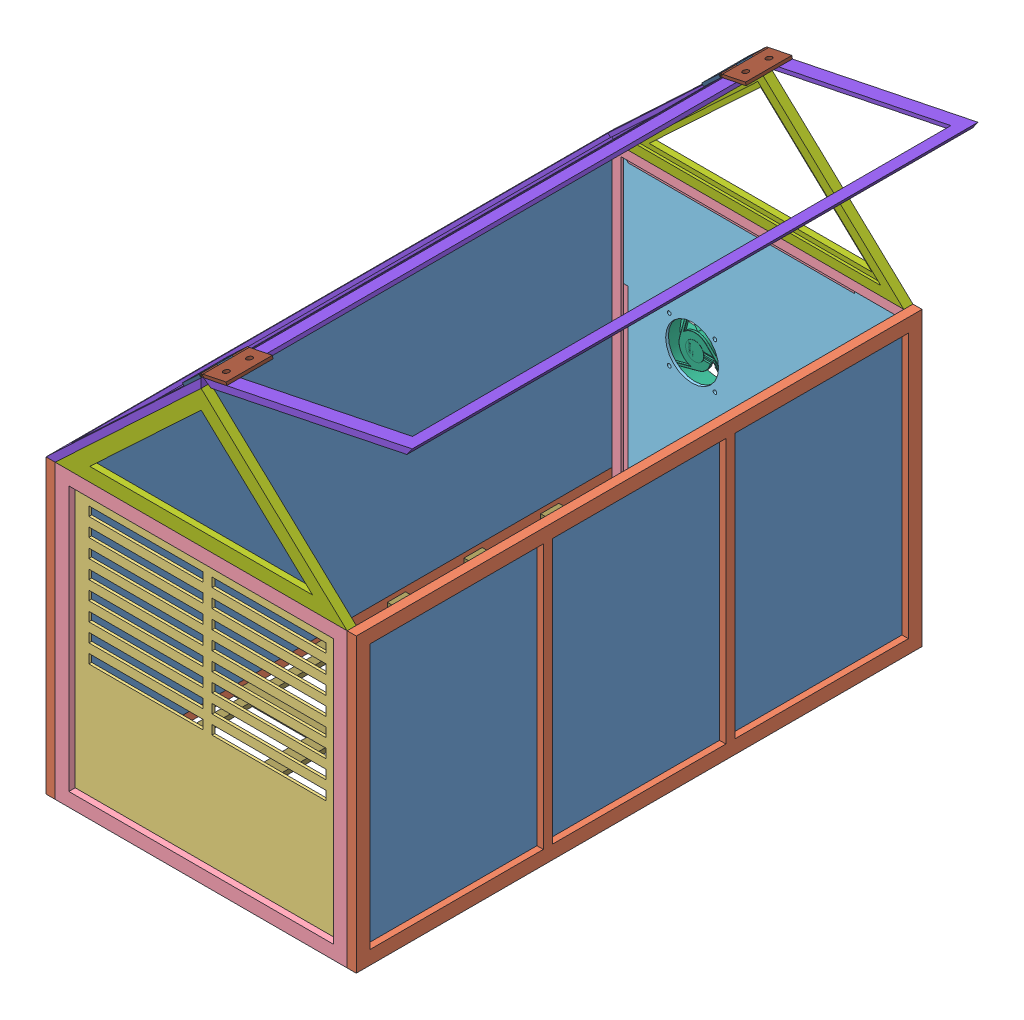
SolidWorks assembly Ensamblaje1, configuration Predeterminado. Lengths in mm.
Overall size (401.19 620.27 664.12).
23 component instances, 12 part files, 53 mates.
Components (placement in the parent):
- Cara lateral-1: Cara lateral [Predeterminado] at (-310 0 606) x (0 0 -1) z (-1 0 0) size (600 300 3)
- Marco lateral-1: Marco lateral [Predeterminado] at (-310 0 606) x (0 0 -1) z (-1 0 0) size (620 320 10)
- Cara Frontal-1: Cara Frontal [Predeterminado] at (0 0 606) x (-1 0 0) z (0 0 1) size (300 300 3)
- Marco Frontal y lateral-1: Marco Frontal y lateral [Predeterminado] at (0 0 606) x (-1 0 0) z (0 0 1) size (320 320 10)
- Marco Frontal y lateral-2: Marco Frontal y lateral [Predeterminado] at (-300 0 6) x (1 0 0) z (0 0 -1) size (320 320 10)
- Marco lateral-2: Marco lateral [Predeterminado] at (10 0 6) x (0 0 1) z (1 0 0) size (620 320 10)
- Cara lateral-2: Cara lateral [Predeterminado] at (13 0 606) x (0 0 -1) z (-1 0 0) size (600 300 3)
- Cara Posterior-1: Cara Posterior [Predeterminado] x (-1 0 0) z (0 0 1) size (300 300 3)
- fan 3inch-1: fan 3inch [Default] at (-75 -150 0) x (-1 0 0) z (0 -1 0) size (82.51 48.37 80)
- fan 3inch-3: fan 3inch [Default] at (-225 -150 0) x (-1 0 0) z (0 -1 0) size (82.51 48.37 80)
- Triangulo superior-1: Triangulo superior [Predeterminado] at (-310 10 606) size (320 150 10)
- Triangulo superior-2: Triangulo superior [Predeterminado] at (10 10 6) x (-1 0 0) z (0 0 -1) size (320 150 10)
- tapa superior-2: tapa superior [Predeterminado] at (-310 10 -4) size (170 160 620)
- tapa superior-3: tapa superior [Predeterminado] at (75.4274 209.9477 615.9039) x (-0.575939 -0.817492 0) z (0 0 -1) size (170 160 620)
- ESAMBLAJE-1: ESAMBLAJE [Predeterminado] at (-149.4075 172.3854 590.5039) x (-0.651352 -0.758775 0) z (0 0 1) size (50.37 22.76 50.9)
  - tornillo 3-1: tornillo 3 [Predeterminado] at (-0.1124 -0.1798 -25.4) size (1.52 1.52 50.8)
  - Placa 1-1: Placa 1 [Predeterminado] at (14.8242 -0.2436 0.0961) x (0 0 1) z (0.994353 -0.106126 0) size (50.8 3.3 29.21)
  - placa 2-1: placa 2 [Predeterminado] at (-12.7879 7.722 0) x (0 0 1) z (-0.790304 0.612716 0) size (50.8 3.3 29.21)
- ESAMBLAJE-2: ESAMBLAJE [Predeterminado] at (-149.4075 172.3854 21.3039) x (-0.651352 -0.758775 0) z (0 0 1) size (50.37 22.76 50.9)
  - tornillo 3-1: tornillo 3 [Predeterminado] at (-0.1124 -0.1798 -25.4) size (1.52 1.52 50.8)
  - Placa 1-1: Placa 1 [Predeterminado] at (14.8242 -0.2436 0.0961) x (0 0 1) z (0.994353 -0.106126 0) size (50.8 3.3 29.21)
  - placa 2-1: placa 2 [Predeterminado] at (-12.7879 7.722 0) x (0 0 1) z (-0.790304 0.612716 0) size (50.8 3.3 29.21)
- Matriz porta materas-1: Matriz porta materas [Predeterminado] at (-72 -240 554) x (0 0 -1) z (1 0 0) size (524 5 188)
Mates (geometry in assembly coordinates):
- Coincidente8: coincident anti-aligned: plane of Cara lateral-1 through (-313 0 6) normal (0 0 -1); plane of Marco lateral-1 through (-313 0 6) normal (0 0 1)
- Coincidente9: coincident anti-aligned: plane of Cara lateral-1 through (-313 0 606) normal (0 1 0); plane of Marco lateral-1 through (-313 0 606) normal (0 -1 0)
- Coincidente10: coincident anti-aligned: plane of Cara lateral-1 through (-313 0 606) normal (-1 0 0); plane of Marco lateral-1 through (-313 0 606) normal (1 0 0)
- Coincidente11: coincident anti-aligned: plane of Marco lateral-1 through (-310 0 606) normal (1 0 0); plane of Marco Frontal y lateral-1 through (-310 10 616) normal (-1 0 0)
- Coincidente12: coincident aligned: plane of Marco lateral-1 through (-320 10 616) normal (0 1 0); plane of Marco Frontal y lateral-1 through (10 10 616) normal (0 1 0)
- Coincidente13: coincident aligned: plane of Marco lateral-1 through (-320 10 616) normal (0 0 1); plane of Marco Frontal y lateral-1 through (0 0 616) normal (0 0 1)
- Coincidente14: coincident anti-aligned: plane of Marco lateral-1 through (-310 0 606) normal (1 0 0); plane of Marco Frontal y lateral-2 through (-310 10 -4) normal (-1 0 0)
- Coincidente15: coincident aligned: plane of Marco lateral-1 through (-320 10 616) normal (0 1 0); plane of Marco Frontal y lateral-2 through (-310 10 -4) normal (0 1 0)
- Coincidente16: coincident aligned: plane of Marco lateral-1 through (-320 10 -4) normal (0 0 -1); plane of Marco Frontal y lateral-2 through (-300 0 -4) normal (0 0 -1)
- Coincidente17: coincident anti-aligned: plane of Marco Frontal y lateral-1 through (10 10 616) normal (1 0 0); plane of Marco lateral-2 through (10 0 6) normal (-1 0 0)
- Coincidente18: coincident aligned: plane of Marco Frontal y lateral-2 through (-300 0 -4) normal (0 0 -1); plane of Marco lateral-2 through (20 10 -4) normal (0 0 -1)
- Coincidente19: coincident aligned: plane of Marco Frontal y lateral-2 through (-310 10 -4) normal (0 1 0); plane of Marco lateral-2 through (20 10 -4) normal (0 1 0)
- Coincidente20: coincident anti-aligned: plane of Cara Frontal-1 through (0 0 609) normal (0 1 0); plane of Marco Frontal y lateral-1 through (0 0 609) normal (0 -1 0)
- Coincidente21: coincident anti-aligned: plane of Cara Frontal-1 through (-300 0 609) normal (-1 0 0); plane of Marco Frontal y lateral-1 through (-300 0 609) normal (1 0 0)
- Coincidente22: coincident anti-aligned: plane of Cara Frontal-1 through (0 0 609) normal (0 0 1); plane of Marco Frontal y lateral-1 through (0 0 609) normal (0 0 -1)
- Coincidente23: coincident anti-aligned: plane of Marco lateral-2 through (13 0 6) normal (-1 0 0); plane of Cara lateral-2 through (13 0 606) normal (1 0 0)
- Coincidente24: coincident anti-aligned: plane of Marco lateral-2 through (13 -300 6) normal (0 1 0); plane of Cara lateral-2 through (10 -300 606) normal (0 -1 0)
- Coincidente25: coincident anti-aligned: plane of Marco lateral-2 through (13 0 6) normal (0 0 1); plane of Cara lateral-2 through (10 0 6) normal (0 0 -1)
- Coincidente26: coincident aligned: plane of Marco Frontal y lateral-2 through (-300 0 3) normal (0 0 1); plane of Cara Posterior-1 through (0 0 3) normal (0 0 1)
- Coincidente27: coincident anti-aligned: plane of Marco Frontal y lateral-2 through (0 0 3) normal (-1 0 0); plane of Cara Posterior-1 through (0 0 3) normal (1 0 0)
- Coincidente28: coincident anti-aligned: plane of Marco Frontal y lateral-2 through (-300 0 3) normal (0 -1 0); plane of Cara Posterior-1 through (0 0 3) normal (0 1 0)
- Concéntrica1: concentric aligned: circle of Cara Posterior-1; circle of fan 3inch-1
- Coincidente30: coincident aligned: plane of Cara Posterior-1 through (0 0 0) normal (0 0 1); plane of assembly through (0 0 0) normal (0 0 1)
- Coincidente31: coincident anti-aligned: plane of Cara Posterior-1 through (0 0 0) normal (0 -1 0); plane of assembly through (0 0 0) normal (0 1 0)
- Coincidente32: coincident anti-aligned: plane of Cara Posterior-1 through (0 0 0) normal (-1 0 0); plane of assembly through (0 0 0) normal (1 0 0)
- Coincidente33: coincident anti-aligned: plane of Cara Posterior-1 through (0 0 0) normal (0 0 -1); plane of fan 3inch-1 through (-35 -110 0) normal (0 0 1)
- Paralelo1: parallel aligned: plane of Marco Frontal y lateral-2 through (-310 -310 -4) normal (0 -1 0); plane of fan 3inch-1 through (-35 -190 -25.5) normal (0 -1 0)
- Concéntrica3: concentric anti-aligned: circle of Cara Posterior-1; circle of fan 3inch-3
- Coincidente39: coincident anti-aligned: plane of Cara Posterior-1 through (0 0 0) normal (0 0 -1); plane of fan 3inch-3 through (-185 -110 0) normal (0 0 1)
- Paralelo4: parallel aligned: plane of Marco Frontal y lateral-2 through (-310 -310 -4) normal (0 -1 0); plane of fan 3inch-3 through (-185 -190 -25.5) normal (0 -1 0)
- Coincidente40: coincident anti-aligned: plane of Marco Frontal y lateral-1 through (10 10 616) normal (0 1 0); plane of Triangulo superior-1 through (-310 10 616) normal (0 -1 0)
- Coincidente41: coincident aligned: line of Marco Frontal y lateral-1 through (-310 10 616) axis (0 0 -1); line of Triangulo superior-1 through (-310 10 616) axis (0 0 -1)
- Coincidente42: coincident anti-aligned: line of Marco Frontal y lateral-1 through (10 10 616) axis (-1 0 0); line of Triangulo superior-1 through (-310 10 616) axis (1 0 0)
- Coincidente43: coincident anti-aligned: plane of Marco Frontal y lateral-2 through (-310 10 -4) normal (0 1 0); plane of Triangulo superior-2 through (10 10 -4) normal (0 -1 0)
- Coincidente44: coincident anti-aligned: line of Marco Frontal y lateral-2 through (-310 10 -4) axis (1 0 0); line of Triangulo superior-2 through (10 10 -4) axis (-1 0 0)
- Coincidente45: coincident aligned: line of Marco Frontal y lateral-2 through (10 10 -4) axis (0 0 1); line of Triangulo superior-2 through (10 10 -4) axis (0 0 1)
- Coincidente62: coincident aligned: plane of Triangulo superior-2 through (10 10 -4) normal (0 0 -1); plane of tapa superior-2 through (-310 10 -4) normal (0 0 -1)
- Coincidente63: coincident anti-aligned: plane of Triangulo superior-2 through (-150 160 -4) normal (-0.683941 0.729537 0); plane of tapa superior-2 through (-310 10 616) normal (0.683941 -0.729537 0)
- Coincidente64: coincident anti-aligned: plane of Marco lateral-1 through (-320 10 616) normal (0 1 0); plane of tapa superior-2 through (-310 10 616) normal (0 -1 0)
- Coincidente66: coincident anti-aligned: plane of tapa superior-2 through (-320 10 616) normal (-0.685365 0.7282 0); plane of ESAMBLAJE-1/Placa 1-1 through (-150 170 565.2) normal (0.685365 -0.7282 0)
- Coincidente67: coincident aligned: line of tapa superior-2 through (-150 170 616) axis (0 0 -1); line of ESAMBLAJE-1/Placa 1-1 through (-150 170 616) axis (0 0 -1)
- Coincidente75: coincident anti-aligned: plane of tapa superior-3 through (81.1868 218.1226 -4.0961) normal (-0.200569 0.97968 0); plane of ESAMBLAJE-1/placa 2-1 through (-147.024 171.4011 565.1039) normal (0.200569 -0.97968 0)
- Coincidente76: coincident aligned: line of tapa superior-3 through (-147.5217 171.2992 -4.0961) axis (0 0 1); line of ESAMBLAJE-1/placa 2-1 through (-147.5217 171.2992 565.1039) axis (0 0 1)
- Coincidente78: coincident aligned: plane of tapa superior-3 through (75.4274 209.9477 615.9039) normal (0 0 1); plane of ESAMBLAJE-1/placa 2-1 through (-122.1401 176.4956 615.9039) normal (0 0 1)
- Coincidente80: coincident anti-aligned: plane of tapa superior-2 through (-320 10 616) normal (-0.685365 0.7282 0); plane of ESAMBLAJE-2/Placa 1-1 through (-150 170 -4) normal (0.685365 -0.7282 0)
- Coincidente81: coincident aligned: line of tapa superior-2 through (-150 170 616) axis (0 0 -1); line of ESAMBLAJE-2/Placa 1-1 through (-150 170 46.8) axis (0 0 -1)
- Coincidente82: coincident anti-aligned: plane of tapa superior-3 through (81.1868 218.1226 -4.0961) normal (-0.200569 0.97968 0); plane of ESAMBLAJE-2/placa 2-1 through (-147.024 171.4011 -4.0961) normal (0.200569 -0.97968 0)
- Coincidente83: coincident aligned: line of tapa superior-3 through (-147.5217 171.2992 -4.0961) axis (0 0 1); line of ESAMBLAJE-2/placa 2-1 through (-147.5217 171.2992 -4.0961) axis (0 0 1)
- Coincidente84: coincident aligned: plane of tapa superior-3 through (75.4274 209.9477 -4.0961) normal (0 0 -1); plane of ESAMBLAJE-2/placa 2-1 through (-122.1401 176.4956 -4.0961) normal (0 0 -1)
- Coincidente85: coincident aligned: plane of tapa superior-2 through (-310 10 -4) normal (0 0 -1); plane of ESAMBLAJE-2/Placa 1-1 through (-170.6723 154.9038 -4) normal (0 0 -1)
- Distancia5: distance = 47 mm: plane of Cara Posterior-1 through (0 0 3) normal (0 0 1); plane of Matriz porta materas-1 through (-156 -235 50) normal (0 0 -1)
- Distancia6: distance = 70 mm: plane of Matriz porta materas-1 through (-72 -240 554) normal (0 -1 0); plane of Marco lateral-2 through (20 -310 -4) normal (0 -1 0)
- Distancia7: distance = 70 mm anti-aligned: plane of Matriz porta materas-1 through (-240 -235 490) normal (-1 0 0); plane of Cara lateral-1 through (-310 0 606) normal (1 0 0)
